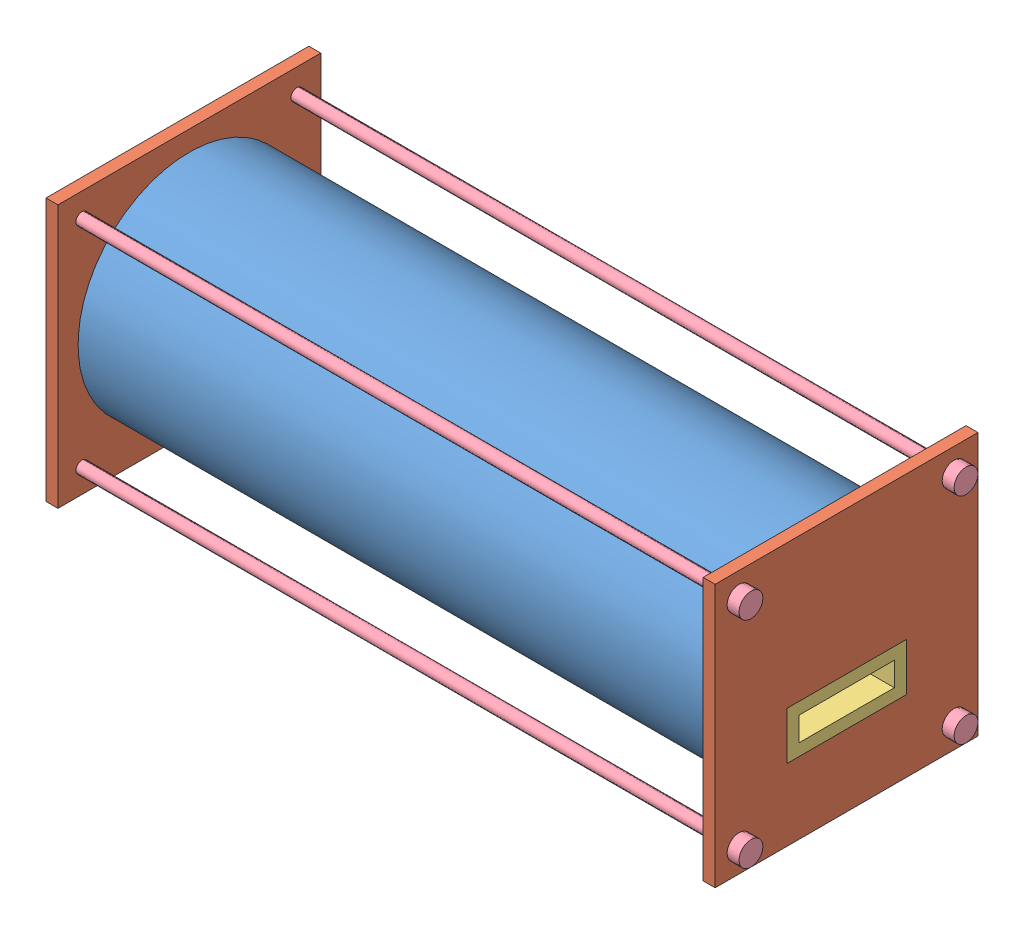
SolidWorks assembly Buoyancy Cylinder Assembly 1, configuration Default. Lengths in mm.
Overall size (580 220 220).
8 component instances, 4 part files, 17 mates.
Components (placement in the parent):
- Cylinder Body 1-1: Cylinder Body 1 [Default] at (-321.7289 98.8857 102.5905) size (550 186.35 186.35)
- End Caps 1-1: End Caps 1 [Default] at (233.2711 -11.1143 -7.4095) x (-1 0 0) z (0 0 -1) size (10 220 220)
- End Caps 1-2: End Caps 1 [Default] at (-326.7289 -11.1143 212.5905) size (10 220 220)
- Water Channel 1-1: Water Channel 1 [Default] at (-326.7289 48.8857 152.5905) size (560 40 100)
- End Cap Bolt 1-1: End Cap Bolt 1 [Default] at (-326.7289 8.8857 192.5905) size (580 20 20)
- End Cap Bolt 1-2: End Cap Bolt 1 [Default] at (-326.7289 188.8857 192.5905) size (580 20 20)
- End Cap Bolt 1-3: End Cap Bolt 1 [Default] at (-326.7289 8.8857 12.5905) size (580 20 20)
- End Cap Bolt 1-4: End Cap Bolt 1 [Default] at (-326.7289 188.8857 12.5905) size (580 20 20)
Mates (geometry in assembly coordinates):
- Coincident1: coincident anti-aligned: plane of Cylinder Body 1-1 through (-321.7289 98.8857 102.5905) normal (-1 0 0); plane of End Caps 1-2 through (-321.7289 98.8857 102.5905) normal (1 0 0)
- Concentric1: concentric anti-aligned: cylinder of Cylinder Body 1-1 through (228.2711 98.8857 102.5905) axis (-1 0 0) radius 93.1728; cylinder of End Caps 1-2 through (-321.7289 98.8857 102.5905) axis (1 0 0) radius 93.1728
- Coincident2: coincident anti-aligned: plane of Cylinder Body 1-1 through (228.2711 98.8857 102.5905) normal (1 0 0); plane of End Caps 1-1 through (228.2711 98.8857 102.5905) normal (-1 0 0)
- Concentric2: concentric aligned: cylinder of Cylinder Body 1-1 through (228.2711 98.8857 102.5905) axis (-1 0 0) radius 93.1728; cylinder of End Caps 1-1 through (228.2711 98.8857 102.5905) axis (-1 0 0) radius 93.1728
- Parallel1: parallel anti-aligned: line of End Caps 1-1 through (233.2711 -11.1143 -7.4095) axis (0 0 1); line of End Caps 1-2 through (-316.7289 -11.1143 212.5905) axis (0 0 -1)
- Coincident4: coincident aligned: plane of End Caps 1-1 through (233.2711 -11.1143 -7.4095) normal (1 0 0); plane of Water Channel 1-1 through (233.2711 48.8857 152.5905) normal (1 0 0)
- Coincident5: coincident anti-aligned: plane of End Caps 1-1 through (223.2711 88.8857 52.5905) normal (0 0 1); plane of Water Channel 1-1 through (233.2711 48.8857 52.5905) normal (0 0 -1)
- Coincident6: coincident anti-aligned: plane of End Caps 1-1 through (223.2711 48.8857 52.5905) normal (0 1 0); plane of Water Channel 1-1 through (233.2711 48.8857 152.5905) normal (0 -1 0)
- Parallel2: parallel: line of End Caps 1-1 through (233.2711 -11.1143 -7.4095) axis (0 0 1); plane of assembly
- Concentric3: concentric: cylinder of End Caps 1-2 through (-326.7289 188.8857 192.5905) axis (1 0 0) radius 5; cylinder of End Cap Bolt 1-2 through (233.2711 188.8857 192.5905) axis (-1 0 0) radius 5
- Coincident7: coincident anti-aligned: plane of End Caps 1-2 through (-326.7289 -11.1143 212.5905) normal (-1 0 0); plane of End Cap Bolt 1-2 through (-326.7289 188.8857 192.5905) normal (1 0 0)
- Concentric4: concentric: cylinder of End Caps 1-1 through (233.2711 188.8857 12.5905) axis (-1 0 0) radius 5; cylinder of End Cap Bolt 1-4 through (233.2711 188.8857 12.5905) axis (-1 0 0) radius 5
- Coincident8: coincident anti-aligned: plane of End Caps 1-1 through (233.2711 -11.1143 -7.4095) normal (1 0 0); plane of End Cap Bolt 1-4 through (233.2711 188.8857 12.5905) normal (-1 0 0)
- Concentric5: concentric: cylinder of End Caps 1-2 through (-326.7289 8.8857 192.5905) axis (1 0 0) radius 5; cylinder of End Cap Bolt 1-1 through (233.2711 8.8857 192.5905) axis (-1 0 0) radius 5
- Coincident9: coincident anti-aligned: plane of End Caps 1-2 through (-326.7289 -11.1143 212.5905) normal (-1 0 0); plane of End Cap Bolt 1-1 through (-326.7289 8.8857 192.5905) normal (1 0 0)
- Concentric6: concentric: cylinder of End Caps 1-2 through (-326.7289 8.8857 12.5905) axis (1 0 0) radius 5; cylinder of End Cap Bolt 1-3 through (233.2711 8.8857 12.5905) axis (-1 0 0) radius 5
- Coincident10: coincident anti-aligned: plane of End Caps 1-2 through (-326.7289 -11.1143 212.5905) normal (-1 0 0); plane of End Cap Bolt 1-3 through (-326.7289 8.8857 12.5905) normal (1 0 0)
